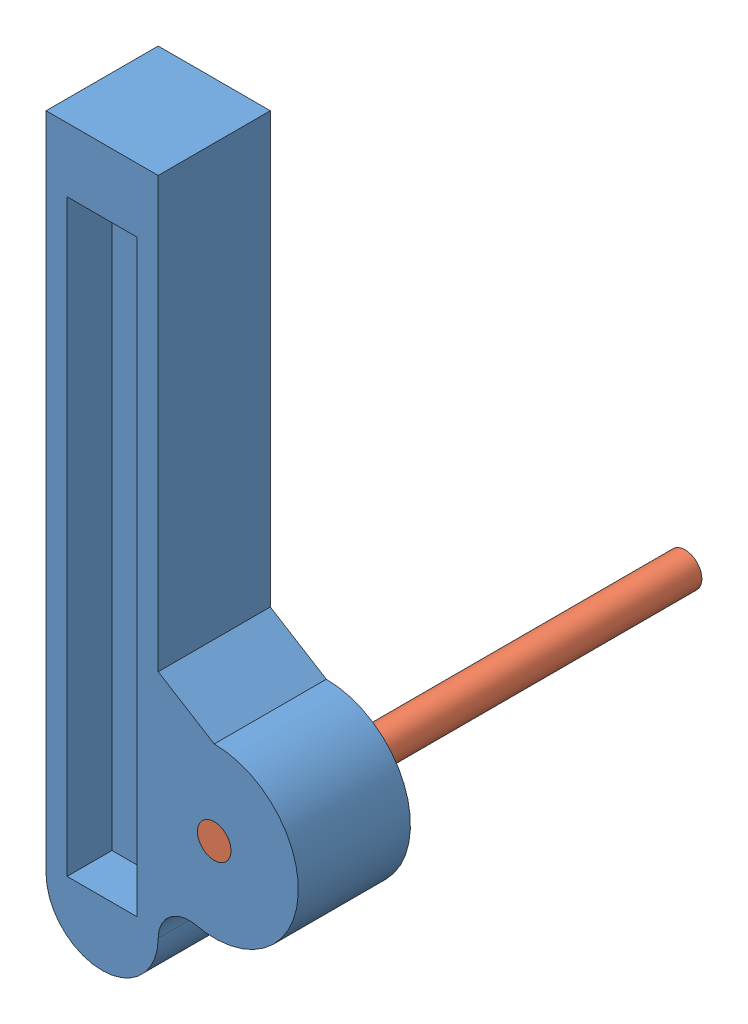
SolidWorks assembly Assem4, configuration Default. Lengths in mm.
Overall size (71.42 127.83 86.5).
2 component instances, 2 part files, 1 mates.
Components (placement in the parent):
- Link3-1: Link3 [Default] at (51.8008 6.1845 -22.147) size (71.42 127.83 22.5)
- shaft2-1: shaft2 [Default] at (51.8008 6.1845 -106.147) size (6 6 84)
Mates (geometry in assembly coordinates):
- Coincident1: coincident aligned: circle of Link3-1; circle of shaft2-1
